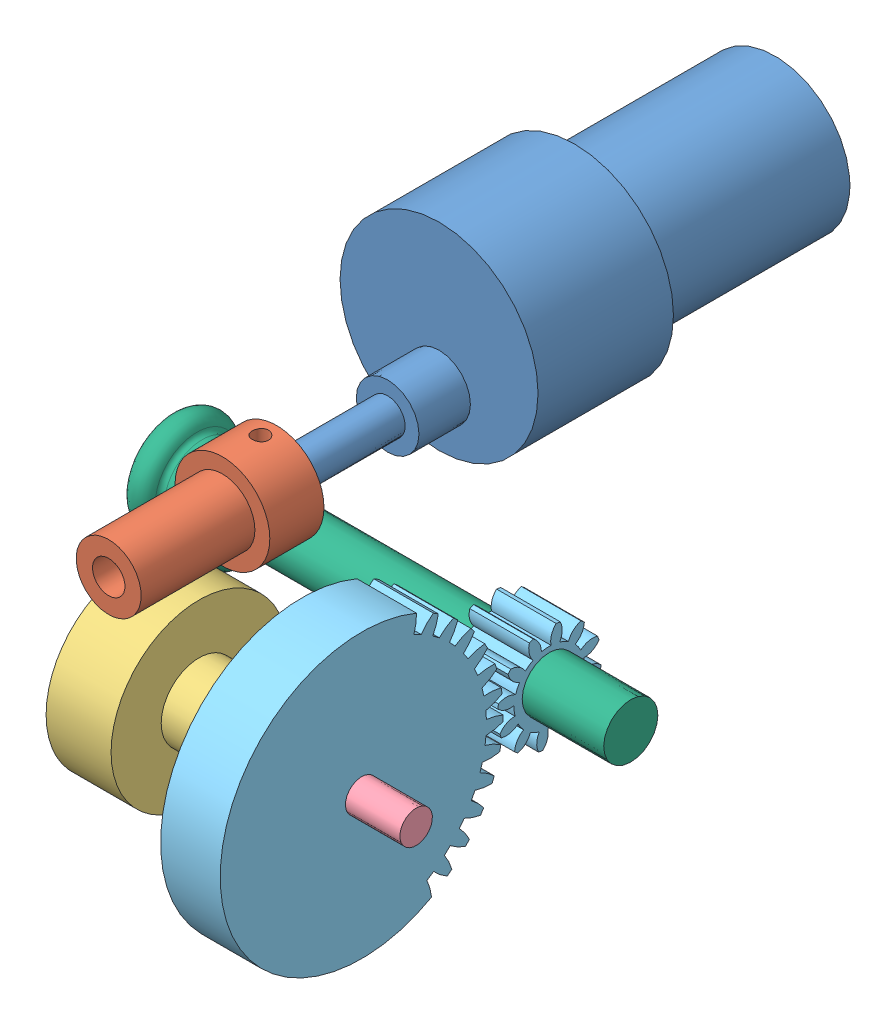
SolidWorks assembly mech assss, configuration Default. Lengths in mm.
Overall size (85 84.66 148.5).
8 component instances, 6 part files, 9 mates.
Components (placement in the parent):
- motor 2-1: motor 2 [Default] at (-20.0328 -8.9413 64.9846) size (36.56 36.56 102.5)
- worm gear part 1-1: worm gear part 1 [Default] at (-20.0328 -16.9313 156.9846) size (17.5 17.5 31)
- worm gear part 2-1: worm gear part 2 [Default] at (-26.0328 -39.1813 177.2924) x (0 0 -1) z (1 0 0) size (32.5 32.5 20)
- shaft between 2pi3 and wom-1: shaft between 2pi3 and wom [Default] at (-33.9558 -39.1813 177.2924) x (0 0.802001 0.597323) z (1 0 0) size (6 6 60)
- gears 1 parts-1: gears 1 parts [Default] at (4.9895 -39.1813 177.2924) x (0 0 -1) z (1 0 0) size (81.08 72.3 27)
  - spur gear_am-2: spur gear_am [Metric - Spur gear 1.375M 36T 14.5PA 11FW ---S12O8H19L6N] x (0 0 1) z (0.834941 0.550339 0) size (19 52.19 52.19)
  - spur gear_am-3: spur gear_am [Metric - Spur gear 1.375M 12T 14.5PA 11FW ---S12B8H27L6N] at (34.6667 0 11) x (0 0 -1) z (0.092549 -0.995708 0) size (27 18.78 18.78)
- pulley-2: pulley [Default] at (-47.5495 -31.8638 144.3817) x (-1 0 0) z (0 0.245825 -0.969314) size (85 19 19)
Mates (geometry in assembly coordinates):
- Concentric2: concentric: cylinder of motor 2-1 through (-20.0328 -16.9313 167.4846) axis (0 0 -1) radius 3.25; cylinder of worm gear part 1-1 through (-20.0328 -16.9313 187.9846) axis (0 0 -1) radius 3
- Concentric3: concentric: cylinder of motor 2-1 through (-20.0328 -28.9413 159.9846) axis (0 1 0) radius 1.5; cylinder of worm gear part 1-1 through (-20.0328 -25.6813 159.9846) axis (0 1 0) radius 1.5
- Tangent2: tangent: cylinder of worm gear part 1-1 through (-20.0328 -16.9313 166.9846) axis (0 0 1) radius 6; cylinder of worm gear part 2-1 through (-6.0328 -39.1813 177.2924) axis (-1 0 0) radius 16.25
- Parallel3: parallel: plane of worm gear part 1-1 through (-20.0328 -16.9313 156.9846) normal (0 0 1); plane of worm gear part 2-1 through (-26.0328 -39.1813 177.2924) normal (0 0 -1)
- Tangent3: tangent: cylinder of worm gear part 1-1 through (-20.0328 -16.9313 166.9846) axis (0 0 1) radius 6; plane of worm gear part 2-1 through (-26.0328 -39.1813 177.2924) normal (-1 0 0)
- Concentric4: concentric: cylinder of worm gear part 2-1 through (-26.0328 -39.1813 177.2924) axis (1 0 0) radius 3; cylinder of shaft between 2pi3 and wom-1 through (26.0442 -39.1813 177.2924) axis (-1 0 0) radius 3
- Concentric5: concentric: cylinder of shaft between 2pi3 and wom-1 through (26.0442 -39.1813 177.2924) axis (-1 0 0) radius 3; cylinder of gears 1 parts-1/spur gear_am-2 through (23.9896 -39.1813 177.2924) axis (-1 0 0) radius 3
- Parallel4: parallel: plane of worm gear part 1-1 through (-20.0328 -16.9313 156.9846) normal (0 0 1); plane of gears 1 parts-1 through (4.9895 -39.1813 177.2924) normal (0 0 -1)
- Distance2: distance = 5 mm: plane of pulley-2 through (-38.9558 -31.8638 144.3817) normal (1 0 0); plane of shaft between 2pi3 and wom-1 through (-33.9558 -39.1813 177.2924) normal (-1 0 0)
